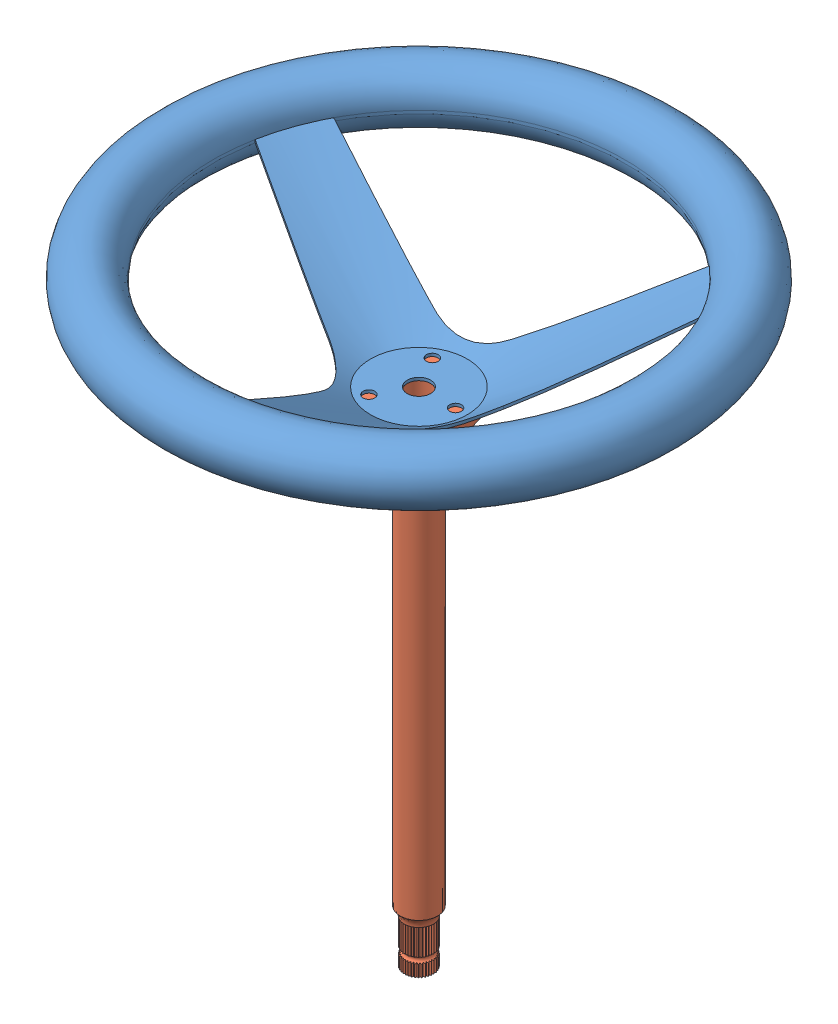
SolidWorks assembly Assem1, configuration Default. Lengths in mm.
Overall size (285.24 337.88 285.24).
2 component instances, 2 part files, 2 mates.
Components (placement in the parent):
- SteeringWheel2022-1: SteeringWheel2022 [Default] at (278.2394 54.8022 213.7224) size (285.24 68.01 285.24)
- SteeringWheelRod2022-1: SteeringWheelRod2022 [Default] at (278.2394 -3.9353 213.7224) x (0.893568 0 0.448927) z (0.448927 0 -0.893568) size (50.8 269.88 50.8)
Mates (geometry in assembly coordinates):
- Coincident3: coincident: plane of SteeringWheel2022-1 through (278.2394 2.4147 213.7224) normal (0 -1 0); plane of SteeringWheelRod2022-1 through (278.2394 2.4147 213.7224) normal (0 1 0)
- Concentric2: concentric aligned: circle of SteeringWheel2022-1; cylinder of SteeringWheelRod2022-1 through (278.2394 -238.8853 213.7224) axis (0 1 0) radius 6.985
